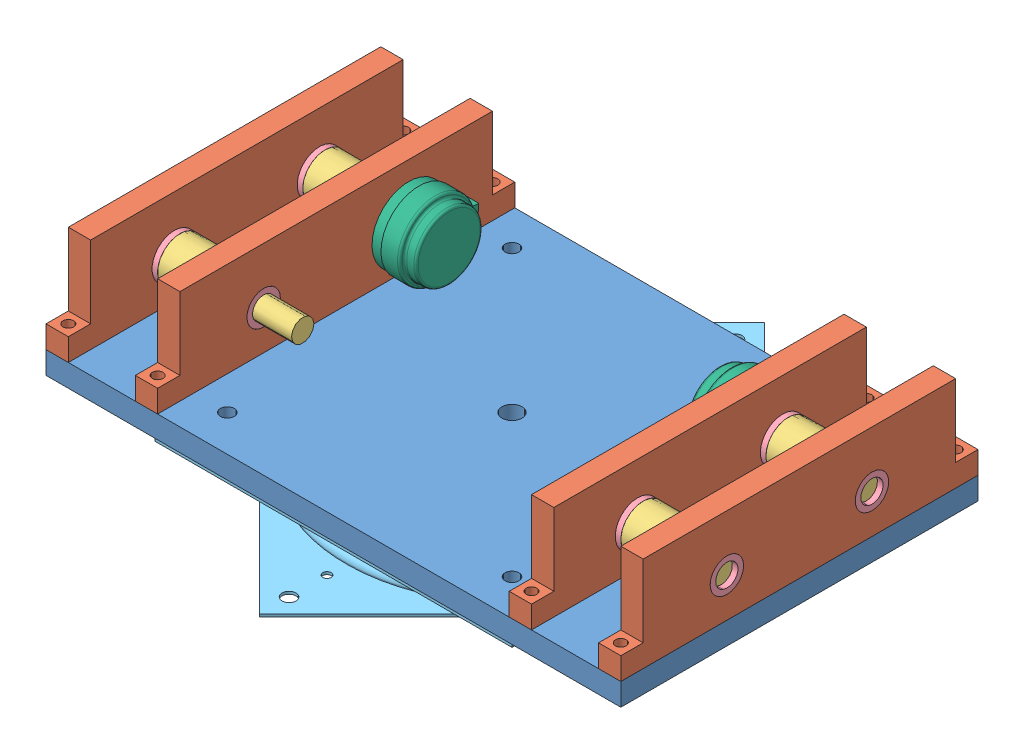
SolidWorks assembly dyno, configuration Default. Lengths in mm.
Overall size (203.2 41.47 203.2).
20 component instances, 6 part files, 43 mates.
Components (placement in the parent):
- dyno_base-1: dyno_base [Default] at (-2.767 23.7054 -14.645) size (163.51 6.35 101.6)
- dyno_block-1: dyno_block [Default] at (-36.3738 30.0554 15.23) x (0 0 -1) z (1 0 0) size (101.6 26.99 6.35)
- dyno_block-2: dyno_block [Default] at (120.7887 30.0554 15.23) x (0 0 -1) z (1 0 0) size (101.6 26.99 6.35)
- dyno_block-3: dyno_block [Default] at (-10.9738 30.0554 15.23) x (0 0 -1) z (1 0 0) size (101.6 26.99 6.35)
- dyno_block-4: dyno_block [Default] at (95.3887 30.0554 15.23) x (0 0 -1) z (1 0 0) size (101.6 26.99 6.35)
- dyno_shaft-1: dyno_shaft [Default] at (89.7827 36.0195 36.1217) x (-1 0 0) z (0 -0.049308 -0.998784) size (41.27 12.7 12.7)
- dyno_shaft-2: dyno_shaft [Default] at (0.9822 38.9212 40.5068) x (1 0 0) z (0 0.900012 0.435865) size (41.27 12.7 12.7)
- dyno_shaft-3: dyno_shaft [Default] at (0.9822 36.0133 -5.4075) size (41.27 12.7 12.7)
- dyno_shaft-4: dyno_shaft [Default] at (89.7827 40.5118 -0.2947) x (-1 0 0) z (0 -0.991868 -0.127273) size (41.27 12.7 12.7)
- dyno_bushing-1: dyno_bushing [Default] at (-4.6238 41.1679 -5.4075) x (-1 0 0) z (0 0.248835 0.968546) size (7.94 12.7 12.7)
- dyno_bushing-2: dyno_bushing [Default] at (95.3887 41.1679 -5.4075) x (1 0 0) z (0 -0.044464 0.999011) size (7.94 12.7 12.7)
- dyno_bushing-3: dyno_bushing [Default] at (-4.6238 41.1679 35.8675) x (-1 0 0) z (0 0.248835 0.968546) size (7.94 12.7 12.7)
- dyno_bushing-4: dyno_bushing [Default] at (95.3887 41.1679 35.8675) x (1 0 0) z (0 -0.044464 0.999011) size (7.94 12.7 12.7)
- dyno_bushing-5: dyno_bushing [Default] at (-36.3738 41.1679 -5.4075) size (7.94 12.7 12.7)
- dyno_bushing-6: dyno_bushing [Default] at (-36.3738 41.1679 35.8675) size (7.94 12.7 12.7)
- dyno_bushing-7: dyno_bushing [Default] at (127.1387 41.1679 -5.4075) x (-1 0 0) z (0 -0.924225 -0.381849) size (7.94 12.7 12.7)
- dyno_bushing-8: dyno_bushing [Default] at (127.1387 41.1679 35.8675) x (-1 0 0) z (0 -0.924225 -0.381849) size (7.94 12.7 12.7)
- turntable-1: turntable [Default] at (45.3824 20.4034 15.23) x (0.707107 0 -0.707107) z (0.707107 0 0.707107) size (143.68 8.13 143.68)
- encoder-1: encoder [Default] at (95.3887 41.1679 -5.4075) x (-1 0 0) z (0 -0.047032 -0.998893) size (11.51 21.64 22.89)
- encoder-2: encoder [Default] at (-4.6238 41.1679 -5.4075) x (1 0 0) z (0 -0.069358 -0.997592) size (11.51 21.64 22.89)
Mates (geometry in assembly coordinates):
- Concentric3: concentric aligned: cylinder of dyno_base-1; cylinder of dyno_block-1
- Concentric4: concentric aligned: cylinder of dyno_base-1; cylinder of dyno_block-1
- Coincident1: coincident anti-aligned: plane of dyno_base-1 through (-36.3738 30.0554 -35.57) normal (0 1 0); plane of dyno_block-1 through (-30.0238 30.0554 15.23) normal (0 -1 0)
- Concentric5: concentric aligned: cylinder of dyno_base-1; cylinder of dyno_block-2
- Concentric6: concentric aligned: cylinder of dyno_base-1; cylinder of dyno_block-2
- Coincident2: coincident anti-aligned: plane of dyno_base-1 through (-36.3738 30.0554 -35.57) normal (0 1 0); plane of dyno_block-2 through (127.1387 30.0554 15.23) normal (0 -1 0)
- Concentric7: concentric anti-aligned: cylinder of dyno_block-1; cylinder of dyno_bushing-6
- Coincident3: coincident anti-aligned: plane of dyno_block-1 through (-30.0238 30.0554 66.03) normal (1 0 0); plane of dyno_bushing-6 through (-30.0238 41.617 35.8675) normal (-1 0 0)
- Concentric8: concentric anti-aligned: cylinder of dyno_block-1; cylinder of dyno_bushing-5
- Coincident4: coincident anti-aligned: plane of dyno_block-1 through (-30.0238 30.0554 66.03) normal (1 0 0); plane of dyno_bushing-5 through (-30.0238 41.617 -5.4075) normal (-1 0 0)
- Concentric9: concentric aligned: cylinder of dyno_block-2; cylinder of dyno_bushing-8
- Coincident5: coincident anti-aligned: plane of dyno_block-2 through (120.7887 30.0554 66.03) normal (-1 0 0); plane of dyno_bushing-8 through (120.7887 41.3394 35.4524) normal (1 0 0)
- Concentric10: concentric aligned: cylinder of dyno_block-2; cylinder of dyno_bushing-7
- Coincident6: coincident anti-aligned: plane of dyno_block-2 through (120.7887 30.0554 66.03) normal (-1 0 0); plane of dyno_bushing-7 through (120.7887 41.3394 -5.8226) normal (1 0 0)
- Concentric11: concentric aligned: cylinder of dyno_shaft-3; cylinder of dyno_bushing-5
- Coincident7: coincident anti-aligned: plane of dyno_shaft-3 through (-28.4363 44.3429 -5.4075) normal (-1 0 0); plane of dyno_bushing-5 through (-28.4363 41.617 -5.4075) normal (1 0 0)
- Concentric12: concentric aligned: cylinder of dyno_shaft-2; cylinder of dyno_bushing-6
- Coincident8: coincident anti-aligned: plane of dyno_shaft-2 through (-28.4363 42.5518 33.01) normal (-1 0 0); plane of dyno_bushing-6 through (-28.4363 41.617 35.8675) normal (1 0 0)
- Concentric13: concentric aligned: cylinder of dyno_shaft-4; cylinder of dyno_bushing-7
- Coincident9: coincident anti-aligned: plane of dyno_shaft-4 through (119.2012 41.572 -8.5567) normal (1 0 0); plane of dyno_bushing-7 through (119.2012 41.3394 -5.8226) normal (-1 0 0)
- Concentric14: concentric aligned: cylinder of dyno_shaft-1; cylinder of dyno_bushing-8
- Coincident10: coincident anti-aligned: plane of dyno_shaft-1 through (119.2012 44.339 35.711) normal (1 0 0); plane of dyno_bushing-8 through (119.2012 41.3394 35.4524) normal (-1 0 0)
- Concentric15: concentric aligned: cylinder of dyno_block-3; cylinder of dyno_bushing-3
- Coincident11: coincident anti-aligned: plane of dyno_block-3 through (-10.9738 30.0554 66.03) normal (-1 0 0); plane of dyno_bushing-3 through (-10.9738 40.7329 35.9793) normal (1 0 0)
- Concentric16: concentric aligned: cylinder of dyno_block-3; cylinder of dyno_bushing-1
- Coincident12: coincident anti-aligned: plane of dyno_block-3 through (-10.9738 30.0554 66.03) normal (-1 0 0); plane of dyno_bushing-1 through (-10.9738 40.7329 -5.2957) normal (1 0 0)
- Concentric17: concentric anti-aligned: cylinder of dyno_block-4; cylinder of dyno_bushing-4
- Coincident13: coincident anti-aligned: plane of dyno_block-4 through (101.7387 30.0554 66.03) normal (1 0 0); plane of dyno_bushing-4 through (101.7387 41.6166 35.8875) normal (-1 0 0)
- Concentric18: concentric anti-aligned: cylinder of dyno_block-4; cylinder of dyno_bushing-2
- Coincident14: coincident anti-aligned: plane of dyno_block-4 through (101.7387 30.0554 66.03) normal (1 0 0); plane of dyno_bushing-2 through (101.7387 41.6166 -5.3875) normal (-1 0 0)
- Concentric19: concentric aligned: cylinder of dyno_base-1; cylinder of dyno_block-3
- Concentric20: concentric aligned: cylinder of dyno_base-1; cylinder of dyno_block-3
- Coincident15: coincident anti-aligned: plane of dyno_base-1 through (-36.3738 30.0554 -35.57) normal (0 1 0); plane of dyno_block-3 through (-4.6238 30.0554 15.23) normal (0 -1 0)
- Concentric21: concentric aligned: cylinder of dyno_base-1; cylinder of dyno_block-4
- Concentric22: concentric aligned: cylinder of dyno_base-1; cylinder of dyno_block-4
- Coincident16: coincident anti-aligned: plane of dyno_base-1 through (-36.3738 30.0554 -35.57) normal (0 1 0); plane of dyno_block-4 through (101.7387 30.0554 15.23) normal (0 -1 0)
- Coincident17: coincident aligned: circle of dyno_base-1; cylinder of turntable-1
- Concentric24: concentric aligned: cylinder of dyno_base-1; cylinder of turntable-1
- Coincident18: coincident anti-aligned: plane of dyno_base-1 through (-36.3738 23.7054 -35.57) normal (0 -1 0); plane of turntable-1 through (78.2115 23.7054 -17.599) normal (0 1 0)
- Concentric25: concentric anti-aligned: cylinder of dyno_shaft-4; cylinder of encoder-1
- Coincident19: coincident anti-aligned: plane of dyno_block-4 through (95.3887 30.0554 66.03) normal (-1 0 0); plane of encoder-1 through (95.3887 42.2335 -5.4576) normal (1 0 0)
- Concentric27: concentric anti-aligned: cylinder of dyno_shaft-3; cylinder of encoder-2
- Coincident21: coincident anti-aligned: plane of dyno_block-3 through (-4.6238 30.0554 66.03) normal (1 0 0); plane of encoder-2 through (-4.6238 40.1037 -5.3335) normal (-1 0 0)
